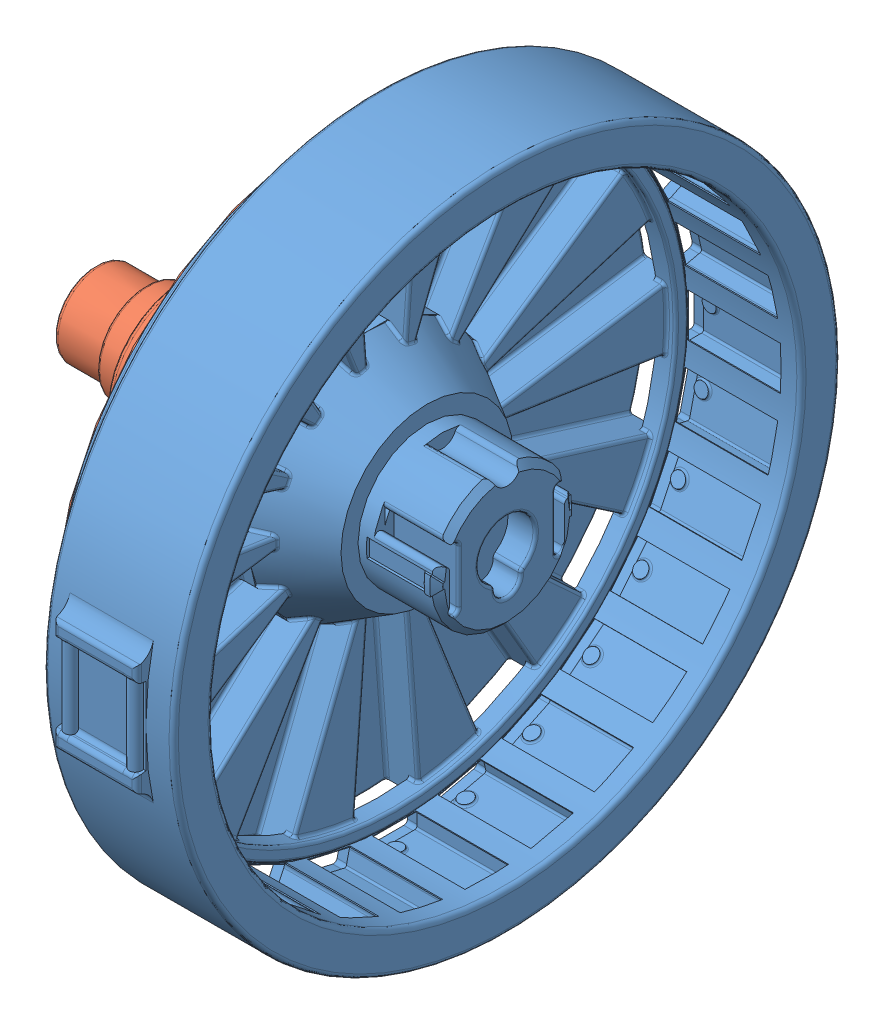
SolidWorks assembly asm_input_motorShaft_240912, configuration По умолчанию. Lengths in mm.
Overall size (78.92 82.28 82.28).
2 component instances, 2 part files, 2 mates.
Components (placement in the parent):
- rotor_70_plus_240403-1: rotor_70_plus_240403 [По умолчанию] at origin size (17.62 72 73.99)
- input_shaf_240912-1: input_shaf_240912 [По умолчанию] at (-19 0 0) x (0 -0.924225 -0.381849) z (1 0 0) size (63 63 78.92)
Mates (geometry in assembly coordinates):
- Совпадение1: coincident aligned: plane of rotor_70_plus_240403-1 through (0 0 0) normal (-1 0 0); plane of input_shaf_240912-1 through (0 0 0) normal (-1 0 0)
- Концентричный1: concentric aligned: cone of rotor_70_plus_240403-1 through (0 0 0) axis (1 0 0); cylinder of input_shaf_240912-1 through (-12 0 0) axis (1 0 0) radius 10
